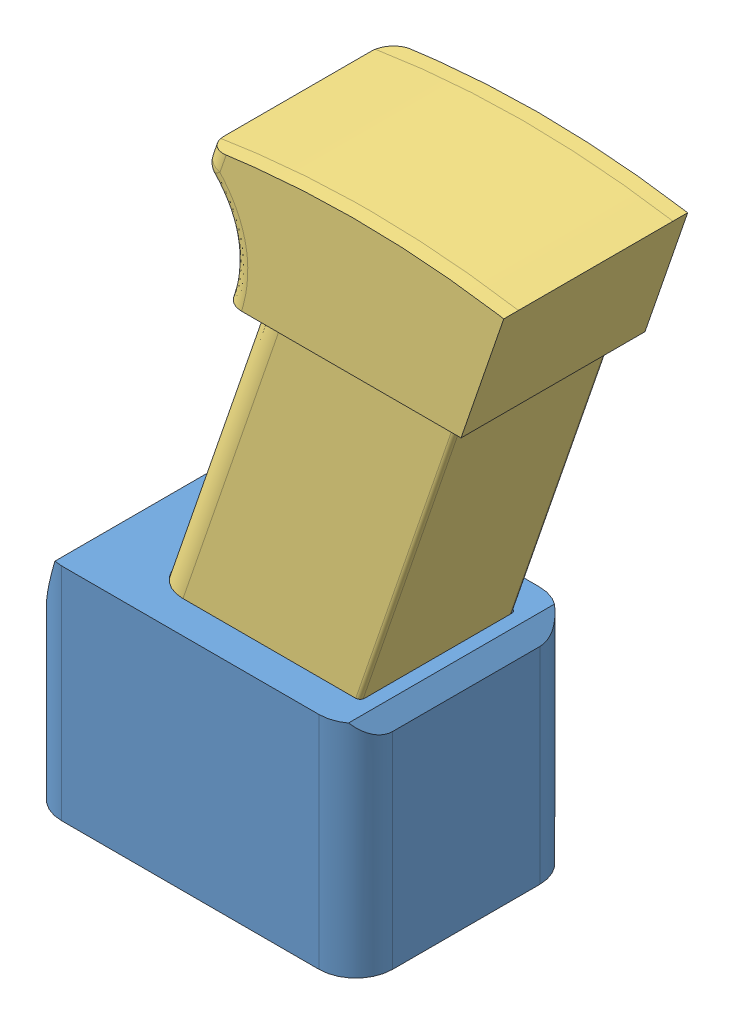
SolidWorks assembly Assemblage, configuration Défaut. Lengths in mm.
Overall size (62.58 89.67 30).
3 component instances, 3 part files, 7 mates.
Components (placement in the parent):
- Base-1: Base [Défaut] at (-23.7829 -14.8673 45) size (45 30 30)
- BMS-1: BMS [Défaut] at (-6.2829 -10.3673 66.05) x (-1 0 0) z (0 -1 0) size (17.5 12.1 4.2)
- Magasine-1: Magasine [Défaut] at (38.8006 73.4709 49.4781) x (-1 -0.000012 0) z (0 0 1) size (57.9 83.31 25.38)
Mates (geometry in assembly coordinates):
- Parallèle2: parallel: plane of Base-1 through (-23.7829 -14.8673 75) normal (-1 0 0); line of Magasine-1 through (-19.1014 -8.5123 66.4781) axis (0 0 -1)
- Tangent1: tangent: curve of Base-1; cylinder of Magasine-1 through (15.9722 81.31 53.4781) axis (-0.324778 -0.94579 0) radius 4
- Coïncidente11: coincident anti-aligned: plane of Base-1 through (9.1328 -8.5123 49.6044) normal (0 1 0); plane of Magasine-1 through (38.8006 -8.5123 70.4781) normal (0 -1 0)
- Coïncidente13: coincident anti-aligned: plane of Base-1 through (-19.7829 -10.3673 66.05) normal (0 -1 0); plane of BMS-1 through (-19.7829 -10.3673 53.95) normal (0 1 0)
- Coïncidente14: coincident aligned: plane of Base-1 through (-23.7829 -14.8673 75) normal (-1 0 0); plane of BMS-1 through (-23.7829 -12.9673 62.85) normal (-1 0 0)
- Coaxiale1: concentric anti-aligned: cylinder of Base-1 through (-19.7829 -10.3673 53.95) axis (0 -1 0) radius 0.4; cylinder of BMS-1 through (-19.7829 -11.3673 53.95) axis (0 1 0) radius 0.6
- Coaxiale2: concentric anti-aligned: cylinder of Base-1 through (-19.7829 -10.3673 66.05) axis (0 -1 0) radius 0.4; cylinder of BMS-1 through (-19.7829 -11.3673 66.05) axis (0 1 0) radius 0.6
